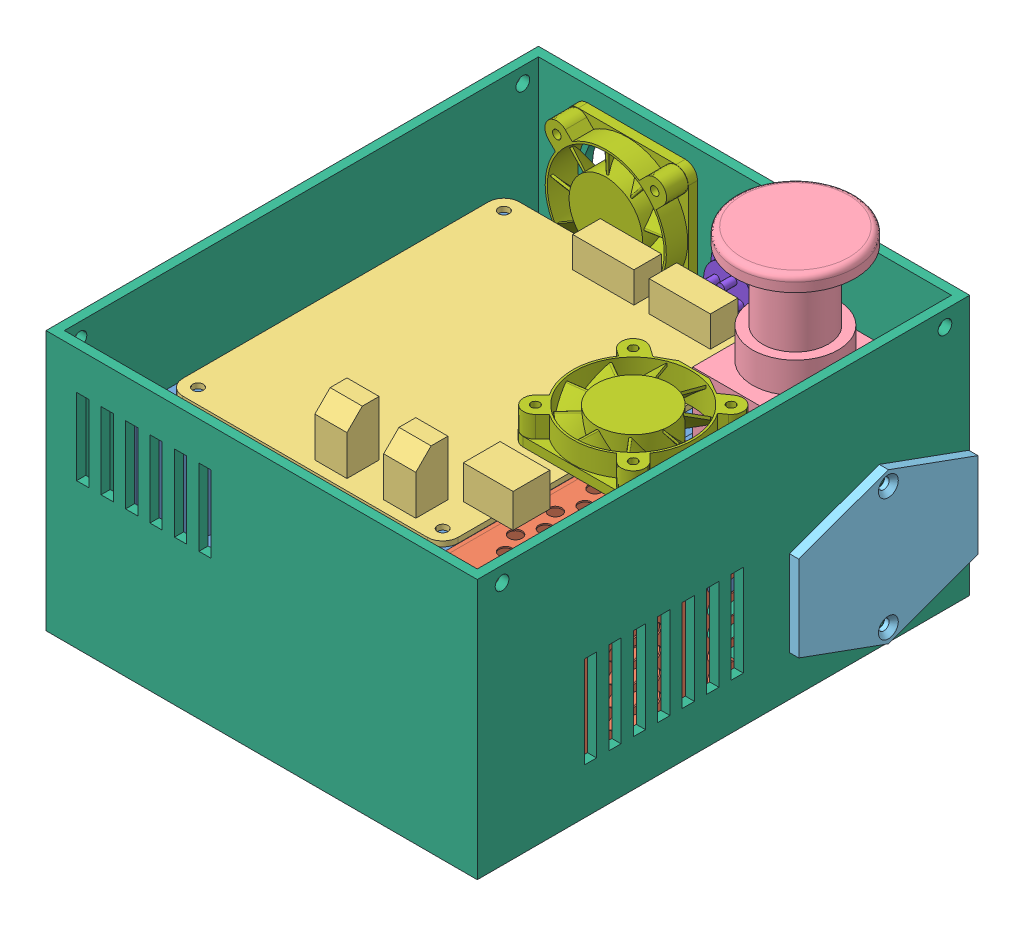
SolidWorks assembly Control_box, configuration Default. Lengths in mm.
Overall size (144 113 169.5).
13 component instances, 9 part files, 30 mates.
Components (placement in the parent):
- Dremel_PSU-1: Dremel_PSU [Default] at (1 0 -4.0629) size (100 50 130)
- PSU-1: PSU [Default] at (51 29.15 18.3371) x (0 -1 0) z (0 0 1) size (58.3 32.7 85.2)
- MKS Base 1.4-1: MKS Base 1.4 [Default] at (4.7 57.1 -6.0629) x (0 0 -1) z (1 0 0) size (110 19.7 97)
- Emergency_stop-1: Emergency_stop [Default] at (68 41.1 -48.0629) size (39 68.9 39)
- AC_plug-1: AC_plug [Default] at (88 24.25 -55.4629) x (0 -1 0) z (0 0 1) size (49.3 30.5 58.6)
- Box-1: Box [Default] at (17.5 -3 -4.5629) size (141 85 161)
- 40x10_fan-1: 40x10_fan [Default] at (-18 57 -82.0629) size (40 40 10.01)
- 40x10_fan-2: 40x10_fan [Default] at (64 72 0.9371) x (-1 0 0) z (0 1 0) size (40 40 10.01)
- GX16-4-1: GX16-4 [Default] at (17.5 52 -85.0629) x (-0.923728 -0.383049 0) z (0.383049 -0.923728 0) size (21.71 21 18.8)
- GX16-4-2: GX16-4 [Default] at (42.5 52 -85.0629) x (-0.923728 -0.383049 0) z (0.383049 -0.923728 0) size (21.71 21 18.8)
- GX16-4-3: GX16-4 [Default] at (42.5 27 -85.0629) x (-0.923728 -0.383049 0) z (0.383049 -0.923728 0) size (21.71 21 18.8)
- GX16-4-4: GX16-4 [Default] at (17.5 27 -85.0629) x (-0.923728 -0.383049 0) z (0.383049 -0.923728 0) size (21.71 21 18.8)
- Lid-1: Lid [Default] at (17.5 82 -4.5629) size (141 15 161) (hidden)
Mates (geometry in assembly coordinates):
- Coincident1: coincident aligned: plane of Dremel_PSU-1 through (1 0 -4.0629) normal (0 -1 0); plane of PSU-1 through (52.3 0 60.9371) normal (0 -1 0)
- Coincident2: coincident anti-aligned: plane of Dremel_PSU-1 through (51 1.3 60.9371) normal (1 0 0); plane of PSU-1 through (51 29.15 18.3371) normal (-1 0 0)
- Coincident3: coincident aligned: plane of Dremel_PSU-1 through (-49 1.3 60.9371) normal (0 0 1); plane of PSU-1 through (52.3 58.3 60.9371) normal (0 0 1)
- Distance1: distance = 7.5 mm anti-aligned: plane of MKS Base 1.4-1 through (4.7 57.1 -6.0629) normal (0 -1 0); plane of Dremel_PSU-1 through (1 49.6 -4.0629) normal (0 1 0)
- Coincident5: coincident anti-aligned: plane of Dremel_PSU-1 through (49.7 50 -69.0629) normal (-1 0 0); plane of MKS Base 1.4-1 through (49.7 58.8 48.9371) normal (1 0 0)
- Distance2: distance = 12 mm aligned: plane of MKS Base 1.4-1 through (49.7 58.8 48.9371) normal (0 0 1); plane of Dremel_PSU-1 through (-49 1.3 60.9371) normal (0 0 1)
- Coincident10: coincident anti-aligned: plane of Dremel_PSU-1 through (1 0 -4.0629) normal (0 -1 0); plane of Box-1 through (17.5 0 -4.5629) normal (0 1 0)
- Coincident16: coincident anti-aligned: plane of Box-1 through (85 82 -82.0629) normal (0 0 1); plane of 40x10_fan-1 through (-18 57 -82.0629) normal (0 0 -1)
- Concentric1: concentric aligned: circle of Box-1; circle of 40x10_fan-1
- Concentric2: concentric aligned: circle of Box-1; circle of 40x10_fan-1
- Concentric3: concentric anti-aligned: circle of AC_plug-1; circle of Box-1
- Concentric4: concentric aligned: circle of AC_plug-1; circle of Box-1
- Concentric5: concentric aligned: circle of Box-1; circle of GX16-4-1
- Coincident20: coincident anti-aligned: plane of Box-1 through (85 82 -82.0629) normal (0 0 1); plane of GX16-4-1 through (17.5 52 -82.0629) normal (0 0 -1)
- Concentric6: concentric aligned: circle of Box-1; circle of GX16-4-2
- Coincident21: coincident anti-aligned: plane of Box-1 through (85 82 -82.0629) normal (0 0 1); plane of GX16-4-2 through (42.5 52 -82.0629) normal (0 0 -1)
- Concentric7: concentric aligned: circle of Box-1; circle of GX16-4-4
- Concentric8: concentric aligned: circle of Box-1; circle of GX16-4-3
- Coincident22: coincident anti-aligned: plane of Box-1 through (85 82 -82.0629) normal (0 0 1); plane of GX16-4-3 through (42.5 27 -82.0629) normal (0 0 -1)
- Coincident23: coincident anti-aligned: plane of Box-1 through (85 82 -82.0629) normal (0 0 1); plane of GX16-4-4 through (17.5 27 -82.0629) normal (0 0 -1)
- Coincident24: coincident aligned: plane of Box-1 through (-53 82 75.9371) normal (0 0 1); plane of Lid-1 through (-53 87 75.9371) normal (0 0 1)
- Coincident25: coincident aligned: plane of Box-1 through (88 82 75.9371) normal (1 0 0); plane of Lid-1 through (88 87 75.9371) normal (1 0 0)
- Coincident26: coincident anti-aligned: plane of Box-1 through (17.5 82 -4.5629) normal (0 1 0); plane of Lid-1 through (17.5 82 -4.5629) normal (0 -1 0)
- Concentric9: concentric aligned: circle of 40x10_fan-2; circle of Lid-1
- Concentric10: concentric aligned: circle of 40x10_fan-2; circle of Lid-1
- Coincident27: coincident anti-aligned: plane of 40x10_fan-2 through (64 82 0.9371) normal (0 1 0); plane of Lid-1 through (17.5 82 -4.5629) normal (0 -1 0)
- Concentric11: concentric aligned: circle of Emergency_stop-1; circle of Lid-1
- Coincident28: coincident anti-aligned: plane of Emergency_stop-1 through (68 82 -48.0629) normal (0 1 0); plane of Lid-1 through (17.5 82 -4.5629) normal (0 -1 0)
- Distance3: distance = 12 mm anti-aligned: plane of Dremel_PSU-1 through (-49 1.3 60.9371) normal (0 0 1); plane of Box-1 through (85 82 72.9371) normal (0 0 -1)
- Distance4: distance = 1 mm anti-aligned: plane of Dremel_PSU-1 through (-49 49.6 -66.0629) normal (-1 0 0); plane of Box-1 through (-50 82 72.9371) normal (1 0 0)
